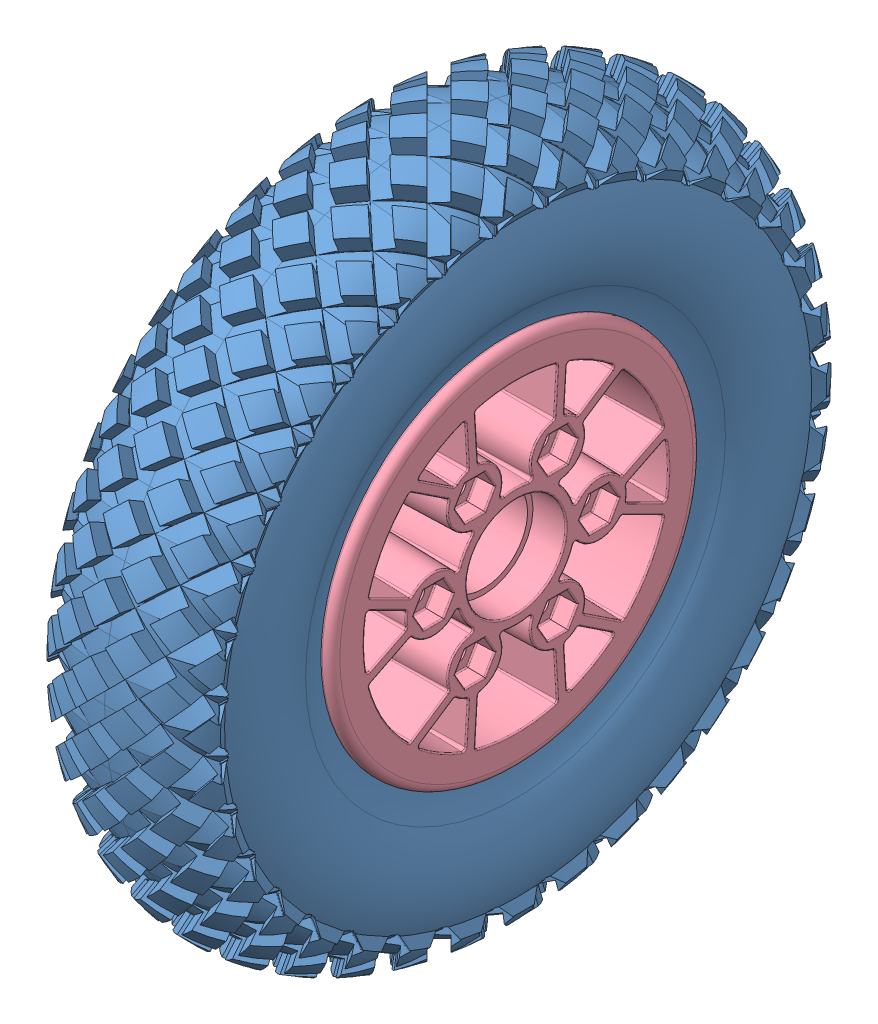
SolidWorks assembly Pneumatic Wheel 8 inch, configuration Default. Lengths in mm.
Overall size (54.46 203.4 203.4).
11 component instances, 4 part files, 0 mates.
Components (placement in the parent):
- Tire-1: Tire [Default] at (-14.0642 3.9407 4.9955) x (0 0 1) z (-1 0 0) size (203.4 203.4 50.81)
- Valve-1: Valve [Default] at (-14.5404 48.2951 4.9955) x (0 1 0) z (0 0 1) size (16.51 34.98 12.8)
- Pneumatic Hub-1: Pneumatic Hub [Default] at (-8.6594 5.0758 -4.0835) size (45.47 106.55 106.55)
  - #4x1.00, Plastic Thread Rolling Screw, Pan Head, Cross Recessed, Zinc Plated (Plastic Applications)_-1: #4x1.00, Plastic Thread Rolling Screw, Pan Head, Cross Recessed, Zinc Plated (Plastic Applications)_ [Default] at (7.3269 34.0601 29.3991) x (-1 0 0) z (0 -0.924225 -0.381849) size (27.43 5.56 5.56)
  - Hub-1: Hub [Default] at (-28.6141 -1.1351 9.0791) size (25.79 106.55 106.55)
  - #4x1.00, Plastic Thread Rolling Screw, Pan Head, Cross Recessed, Zinc Plated (Plastic Applications)_-2: #4x1.00, Plastic Thread Rolling Screw, Pan Head, Cross Recessed, Zinc Plated (Plastic Applications)_ [Default] at (7.3269 -1.1351 -31.5609) x (-1 0 0) z (0 0.131421 0.991327) size (27.43 5.56 5.56)
  - #4x1.00, Plastic Thread Rolling Screw, Pan Head, Cross Recessed, Zinc Plated (Plastic Applications)_-3: #4x1.00, Plastic Thread Rolling Screw, Pan Head, Cross Recessed, Zinc Plated (Plastic Applications)_ [Default] at (-19.0891 -1.1351 49.7191) x (1 0 0) z (0 -0.750107 0.661316) size (27.43 5.56 5.56)
  - #4x1.00, Plastic Thread Rolling Screw, Pan Head, Cross Recessed, Zinc Plated (Plastic Applications)_-4: #4x1.00, Plastic Thread Rolling Screw, Pan Head, Cross Recessed, Zinc Plated (Plastic Applications)_ [Default] at (7.3269 -36.3304 29.3991) x (-1 0 0) z (0 0.792804 -0.609477) size (27.43 5.56 5.56)
  - #4x1.00, Plastic Thread Rolling Screw, Pan Head, Cross Recessed, Zinc Plated (Plastic Applications)_-5: #4x1.00, Plastic Thread Rolling Screw, Pan Head, Cross Recessed, Zinc Plated (Plastic Applications)_ [Default] at (-19.0891 34.0601 -11.2409) x (1 0 0) z (0 0.94777 0.318954) size (27.43 5.56 5.56)
  - #4x1.00, Plastic Thread Rolling Screw, Pan Head, Cross Recessed, Zinc Plated (Plastic Applications)_-6: #4x1.00, Plastic Thread Rolling Screw, Pan Head, Cross Recessed, Zinc Plated (Plastic Applications)_ [Default] at (-19.0891 -36.3304 -11.2409) x (1 0 0) z (0 -0.197663 -0.98027) size (27.43 5.56 5.56)
  - Hub-2: Hub [Default] at (16.8519 -1.1351 9.0791) x (-1 0 0) z (0 0 -1) size (25.79 106.55 106.55)
